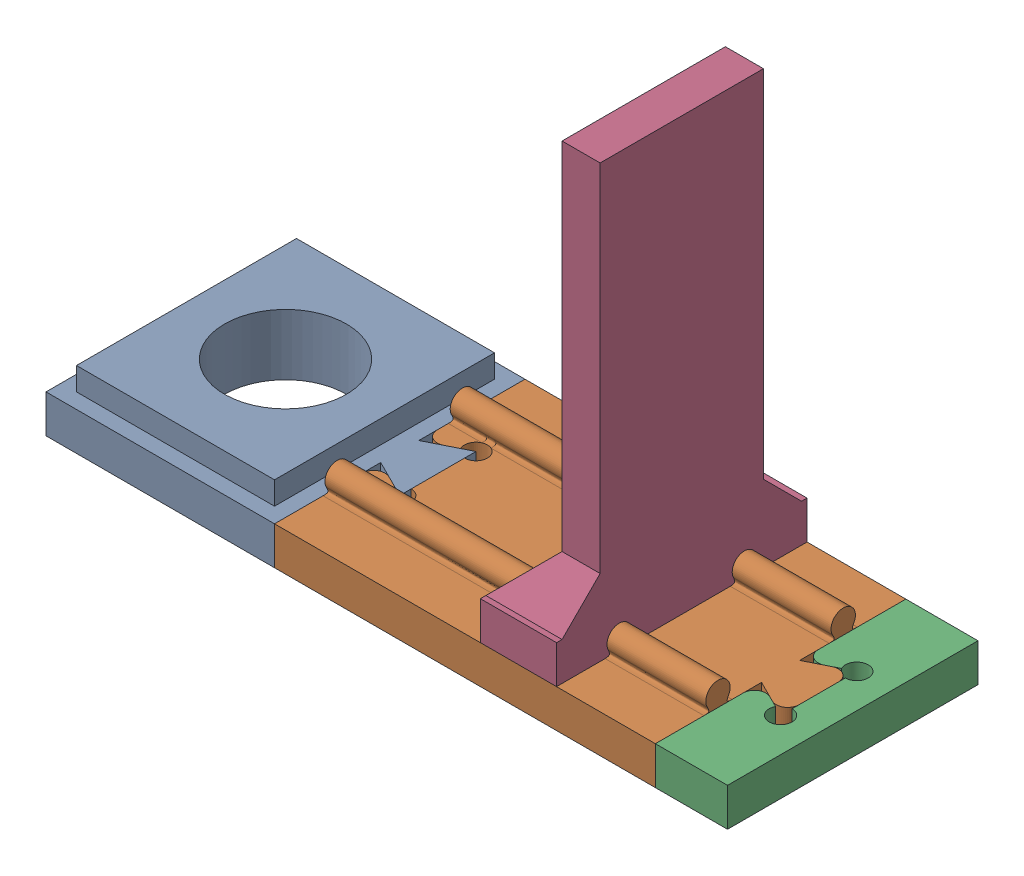
SolidWorks assembly 2.2.2.1_Mono_Guia_Lineal, configuration Predeterminado. Lengths in mm.
Overall size (89.47 61.68 32.88).
4 component instances, 4 part files, 10 mates.
Components (placement in the parent):
- 2.1.2.2.6_Base_Sujetador-1: 2.1.2.2.6_Base_Sujetador [Predeterminado] at (-44.4459 -5.7383 3.6115) x (-1 0 0) z (0 -1 0) size (35 32.88 8)
- 2.1.2.2.7_Segmento_Riel-1: 2.1.2.2.7_Segmento_Riel [Predeterminado] at (-54.4459 -13.7383 3.6115) x (-1 0 0) z (0 -1 0) size (55.01 32.88 8.1)
- 2.1.2.2.8_Segmento_Final_De_Riel-1: 2.1.2.2.8_Segmento_Final_De_Riel [Predeterminado] at (-54.4459 -13.7383 3.6115) x (-1 0 0) z (0 -1 0) size (9.47 32.88 5)
- 2.1.2.2.9_Pared_De_Rebote-1: 2.1.2.2.9_Pared_De_Rebote [Predeterminado] at (-3.4196 -13.7383 3.6115) x (0 -1 0) z (1 0 0) size (56.68 32.88 10.01)
Mates (geometry in assembly coordinates):
- Paralelo1: parallel anti-aligned: plane of 2.1.2.2.6_Base_Sujetador-1 through (-44.4459 -13.7383 3.6115) normal (0 -1 0)
- Paralelo2: parallel aligned: plane of 2.1.2.2.6_Base_Sujetador-1 through (-40.4459 -13.7383 10.8963) normal (0 0 1)
- Coincidente3: coincident anti-aligned: plane of 2.1.2.2.6_Base_Sujetador-1 through (-35.4459 -8.7383 -10.5461) normal (-0.447214 0 -0.894427); plane of 2.1.2.2.7_Segmento_Riel-1 through (-56.309 55.3429 -0.1146) normal (0.447214 0 0.894427)
- Coincidente4: coincident anti-aligned: plane of 2.1.2.2.6_Base_Sujetador-1 through (-35.4459 -8.7383 -0.5461) normal (-0.447214 0 0.894427); plane of 2.1.2.2.7_Segmento_Riel-1 through (-48.9829 55.3429 -7.3146) normal (0.447214 0 -0.894427)
- Coincidente5: coincident aligned: plane of 2.1.2.2.6_Base_Sujetador-1 through (-44.4459 -8.7383 3.6115) normal (0 1 0); plane of 2.1.2.2.7_Segmento_Riel-1 through (-54.4459 -8.7383 3.6115) normal (0 1 0)
- Coincidente6: coincident anti-aligned: plane of 2.1.2.2.7_Segmento_Riel-1 through (-38.9829 55.3429 -27.3146) normal (-0.447214 0 0.894427); plane of 2.1.2.2.8_Segmento_Final_De_Riel-1 through (13.2124 25.4832 -1.2169) normal (0.447214 0 -0.894427)
- Coincidente7: coincident anti-aligned: plane of 2.1.2.2.7_Segmento_Riel-1 through (-46.309 55.3429 19.8854) normal (-0.447214 0 -0.894427); plane of 2.1.2.2.8_Segmento_Final_De_Riel-1 through (11.7249 25.4832 -9.1315) normal (0.447214 0 0.894427)
- Coincidente8: coincident aligned: plane of 2.1.2.2.7_Segmento_Riel-1 through (-54.4459 -8.7383 3.6115) normal (0 1 0); plane of 2.1.2.2.8_Segmento_Final_De_Riel-1 through (-54.4459 -8.7383 3.6115) normal (0 1 0)
- Concéntrica1: concentric aligned: cylinder of 2.1.2.2.7_Segmento_Riel-1 through (-44.9714 -7.2383 2.6751) axis (1 0 0) radius 1.6; cylinder of 2.1.2.2.9_Pared_De_Rebote-1 through (-13.4196 -7.2383 2.6751) axis (1 0 0) radius 1.6
- Concéntrica2: concentric aligned: cylinder of 2.1.2.2.7_Segmento_Riel-1 through (-44.9714 -7.2383 -13.7673) axis (1 0 0) radius 1.6; cylinder of 2.1.2.2.9_Pared_De_Rebote-1 through (-13.4196 -7.2383 -13.7673) axis (1 0 0) radius 1.6
